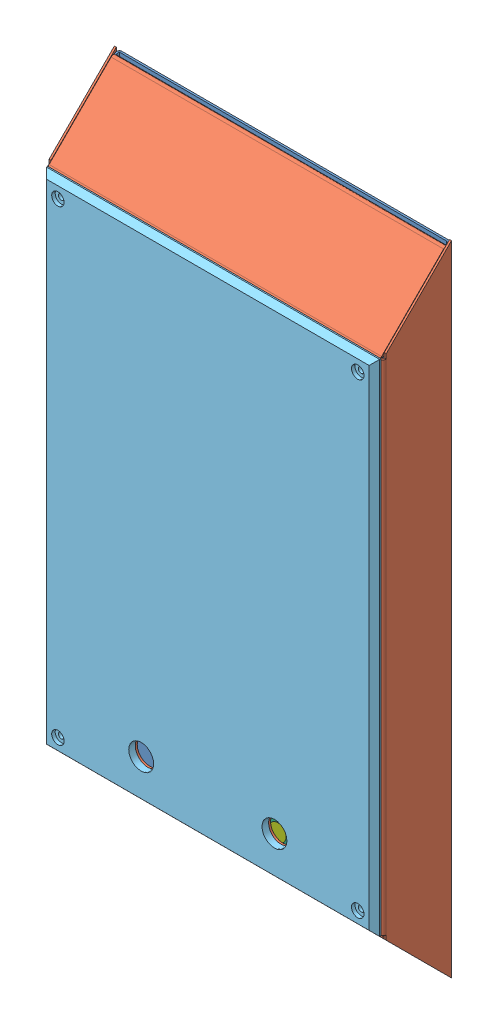
SolidWorks assembly Water ATm, configuration Default. Lengths in mm.
Overall size (257 486.84 103.3).
10 component instances, 8 part files, 19 mates.
Components (placement in the parent):
- backplate 2-1: backplate 2 [Default] at (-12.6462 -5.6883 10.5377) size (254 482.6 47.22)
- Back Plate-1: Back Plate [Default] at (-12.6462 -5.6883 61.3377) size (257 486.84 52.3)
- Arcylic-1: Arcylic [Default] at (-12.6462 -31.1225 61.3377) x (-1 0 0) z (0 0 -1) size (203.2 203.2 4)
- LEDhousing-1: LEDhousing [Default] at (-12.6462 -31.1225 37.2877) x (-1 0 0) z (0 0 -1) size (228.6 228.6 20.05)
- plexiglas-1: plexiglas [Default] at (-12.6302 -5.2741 62.8377) size (254 381 5)
- lock-1: lock [Default] at (-88.8462 -215.1416 12.5377) x (0.999898 -0.014294 0) z (0 0 1) size (19.05 50.8 2)
- lock-2: lock [Default] at (-12.6462 -215.1416 12.5377) x (0.999898 -0.014294 0) z (0 0 1) size (19.05 50.8 2)
- lock-3: lock [Default] at (63.5538 -215.1416 12.5377) x (0.999898 -0.014294 0) z (0 0 1) size (19.05 50.8 2)
- Locking Rod-1: Locking Rod [Default] at (-12.6462 -215.1416 -35.4623) x (0.993629 0.1127 0) z (0 0 1) size (12.7 12.7 50)
- linkingrod-1: linkingrod [Default] at (-55.7777 -194.7436 18.5377) size (177.8 10 2)
Mates (geometry in assembly coordinates):
- Coincident1: coincident anti-aligned: plane of backplate 2-1 through (114.3538 -5.6883 10.5377) normal (1 0 0); plane of Back Plate-1 through (114.3538 -5.6883 61.3377) normal (-1 0 0)
- Coincident2: coincident anti-aligned: plane of backplate 2-1 through (-12.6462 -5.6883 10.5377) normal (0 0 1); plane of Back Plate-1 through (-12.6462 -7.1883 10.5377) normal (0 0 -1)
- Distance2: distance = 1.5 mm aligned: plane of Back Plate-1 through (115.8538 -199.3096 60.3377) normal (0 -0.707107 0.707107); plane of backplate 2-1 through (114.3538 -201.2683 56.2577) normal (0 -0.707107 0.707107)
- Coincident6: coincident anti-aligned: plane of Back Plate-1 through (114.3538 -196.1883 61.3377) normal (0 0 -1); plane of Arcylic-1 through (-12.6462 -31.1225 61.3377) normal (0 0 1)
- Distance3: distance = 6.35 mm anti-aligned: plane of Arcylic-1 through (88.9538 70.4775 57.3377) normal (1 0 0); plane of Back Plate-1 through (82.6038 64.1275 61.3377) normal (-1 0 0)
- Distance4: distance = 6.35 mm anti-aligned: plane of Arcylic-1 through (88.9538 70.4775 57.3377) normal (0 1 0); plane of Back Plate-1 through (-6.2962 64.1275 61.3377) normal (0 -1 0)
- Distance5: distance = 4 mm anti-aligned: plane of LEDhousing-1 through (-990.5462 57.7775 57.3377) normal (0 0 1); plane of Back Plate-1 through (114.3538 -196.1883 61.3377) normal (0 0 -1)
- Distance6: distance = 12.7 mm aligned: plane of LEDhousing-1 through (-990.5462 83.1775 57.3377) normal (0 1 0); plane of Arcylic-1 through (88.9538 70.4775 57.3377) normal (0 1 0)
- Distance7: distance = 12.7 mm aligned: plane of Arcylic-1 through (-114.2462 70.4775 57.3377) normal (-1 0 0); plane of LEDhousing-1 through (-126.9462 -1009.0225 57.3377) normal (-1 0 0)
- Concentric1: concentric aligned: circle of Back Plate-1; cylinder of plexiglas-1 through (101.6698 172.5259 67.8377) axis (0 0 1) radius 2.2479
- Concentric2: concentric aligned: cylinder of Back Plate-1 through (-126.9302 172.5259 62.8377) axis (0 0 1) radius 2.25; cylinder of plexiglas-1 through (-126.9302 172.5259 67.8377) axis (0 0 1) radius 2.2479
- Coincident12: coincident anti-aligned: plane of Back Plate-1 through (114.3538 -196.1883 62.8377) normal (0 0 1); plane of plexiglas-1 through (-12.6302 -5.2741 62.8377) normal (0 0 -1)
- Concentric3: concentric aligned: cylinder of backplate 2-1 through (-88.8462 -215.1416 17.5377) axis (0 0 -1) radius 6.35; cylinder of lock-1 through (-88.8462 -215.1416 14.5377) axis (0 0 -1) radius 6.35
- Coincident13: coincident anti-aligned: plane of backplate 2-1 through (-12.6462 -5.6883 12.5377) normal (0 0 1); plane of lock-1 through (-88.8462 -215.1416 12.5377) normal (0 0 -1)
- Concentric4: concentric aligned: cylinder of lock-2 through (-12.6462 -215.1416 14.5377) axis (0 0 -1) radius 6.35; cylinder of Locking Rod-1 through (-12.6462 -215.1416 14.5377) axis (0 0 -1) radius 6.35
- Coincident15: coincident aligned: plane of lock-2 through (-12.6462 -215.1416 14.5377) normal (0 0 1); plane of Locking Rod-1 through (-12.6462 -215.1416 14.5377) normal (0 0 1)
- Concentric5: concentric anti-aligned: cylinder of lock-1 through (-88.5546 -194.7436 12.5377) axis (0 0 -1) radius 2.5; cylinder of linkingrod-1 through (-88.5546 -194.7436 20.5377) axis (0 0 1) radius 2.5
- Distance8: distance = 4 mm anti-aligned: plane of lock-1 through (-88.8462 -215.1416 14.5377) normal (0 0 1); plane of linkingrod-1 through (-55.7777 -194.7436 18.5377) normal (0 0 -1)
- Concentric6: concentric anti-aligned: cylinder of lock-3 through (63.8454 -194.7436 12.5377) axis (0 0 -1) radius 2.5; cylinder of linkingrod-1 through (63.8454 -194.7436 20.5377) axis (0 0 1) radius 2.5
